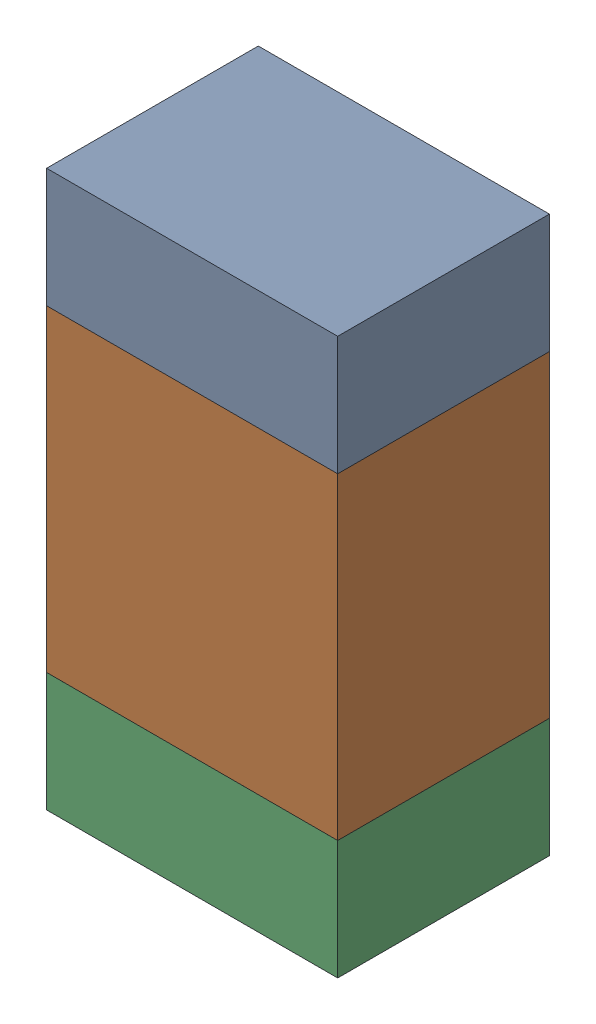
SolidWorks assembly R308_2PCB, configuration Default. Lengths in mm.
Overall size (0.55 1.05 0.4).
6 component instances, 2 part files, 0 mates.
Components (placement in the parent):
- 846483288-1: 846483288 [Default] at (128.3001 95.2124 0) size (0.55 0.22 0.4)
  - Extruded_12-1: Extruded_12 [Default] at origin size (0.55 0.22 0.4)
- 846483424-1: 846483424 [Default] at (128.3001 94.7999 0) size (0.55 0.6 0.4)
  - Extruded_13-1: Extruded_13 [Default] at origin size (0.55 0.6 0.4)
- 846483288-2: 846483288 [Default] at (128.3001 94.3874 0) size (0.55 0.22 0.4)
  - Extruded_12-1: Extruded_12 [Default] at origin size (0.55 0.22 0.4)
